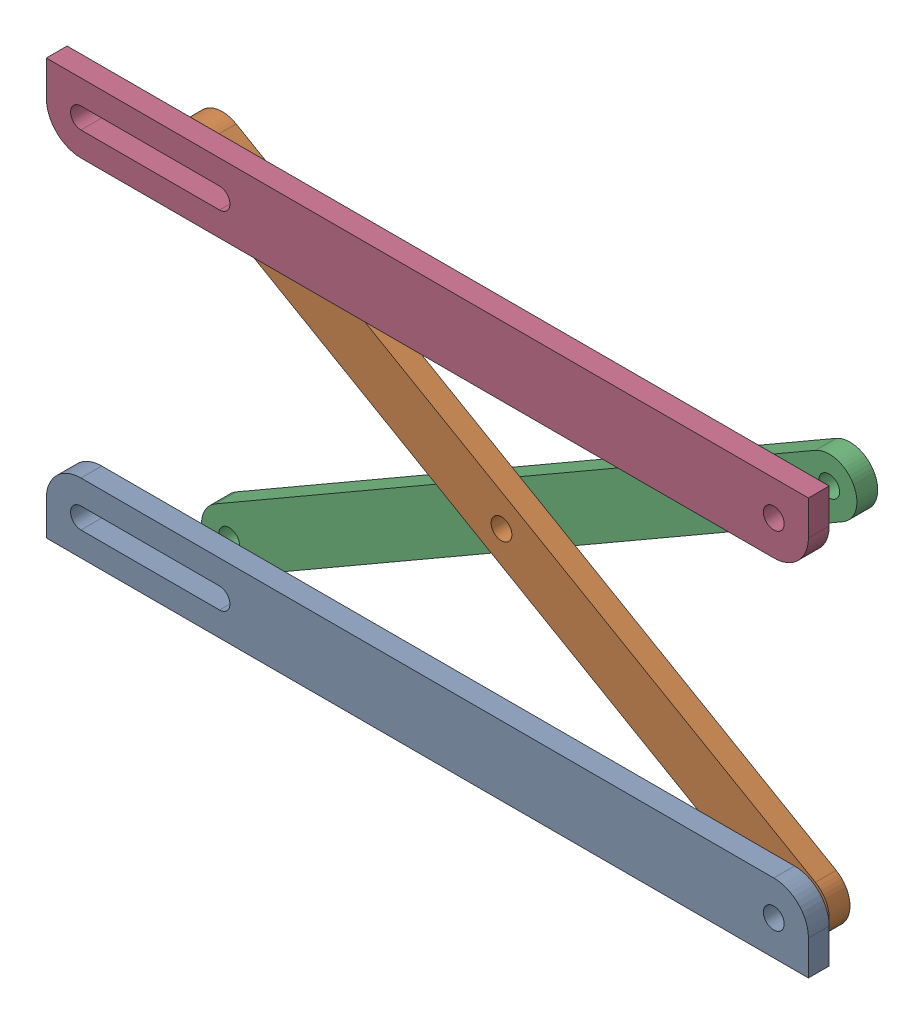
SolidWorks assembly ParallelLinkage, configuration Default. Lengths in mm.
Overall size (110.46 60.93 11).
4 component instances, 2 part files, 10 mates.
Components (placement in the parent):
- HorizontalLink-1: HorizontalLink [Default] at origin size (110 10 3)
- Link-1: Link [Default] at (6.6987 25 -4) x (0.866025 -0.5 0) z (0 0 1) size (108 8 3)
- Link-2: Link [Default] at (6.6987 25 -8) x (0.866025 0.5 0) z (0 0 1) size (108 8 3)
- HorizontalLink-2: HorizontalLink [Default] at (0 50 3) x (1 0 0) z (0 0 -1) size (110 10 3)
Mates (geometry in assembly coordinates):
- Concentric1: concentric aligned: cylinder of HorizontalLink-1 through (50 0 3) axis (0 0 -1) radius 1.5; cylinder of Link-1 through (50 0 -1) axis (0 0 -1) radius 1.5
- Distance1: distance = 1 mm anti-aligned: plane of Link-1 through (6.6987 25 -1) normal (0 0 1); plane of HorizontalLink-1 through (-50 0 0) normal (0 0 -1)
- Tangent1: tangent anti-aligned: plane of HorizontalLink-1 through (-50 -1.5 3) normal (0 1 0); cylinder of Link-2 through (-36.6025 0 -5) axis (0 0 -1) radius 1.5
- Distance2: distance = 1 mm anti-aligned: plane of Link-2 through (6.6987 25 -5) normal (0 0 1); plane of Link-1 through (6.6987 25 -4) normal (0 0 -1)
- Concentric2: concentric aligned: cylinder of Link-1 through (6.6987 25 -1) axis (0 0 -1) radius 1.5; cylinder of Link-2 through (6.6987 25 -5) axis (0 0 -1) radius 1.5
- Distance4: distance = 1 mm anti-aligned: plane of Link-1 through (6.6987 25 -1) normal (0 0 1); plane of HorizontalLink-2 through (-50 50 0) normal (0 0 -1)
- Concentric3: concentric anti-aligned: cylinder of Link-2 through (50 50 -5) axis (0 0 -1) radius 1.5; cylinder of HorizontalLink-2 through (50 50 0) axis (0 0 1) radius 1.5
- Tangent2: tangent anti-aligned: cylinder of Link-1 through (-36.6025 50 -1) axis (0 0 -1) radius 1.5; plane of HorizontalLink-2 through (-50 48.5 0) normal (0 1 0)
- LimitAngle3: limit planar angle = 0.523599 rad aligned: plane of Link-1 through (8.6987 28.4641 -1) normal (0.5 0.866025 0); plane of HorizontalLink-1 through (50 5 3) normal (0 1 0)
- LimitDistance1: limit distance = 40 mm anti-aligned: plane of HorizontalLink-1 through (50 5 3) normal (0 1 0); plane of HorizontalLink-2 through (50 45 0) normal (0 -1 0)
